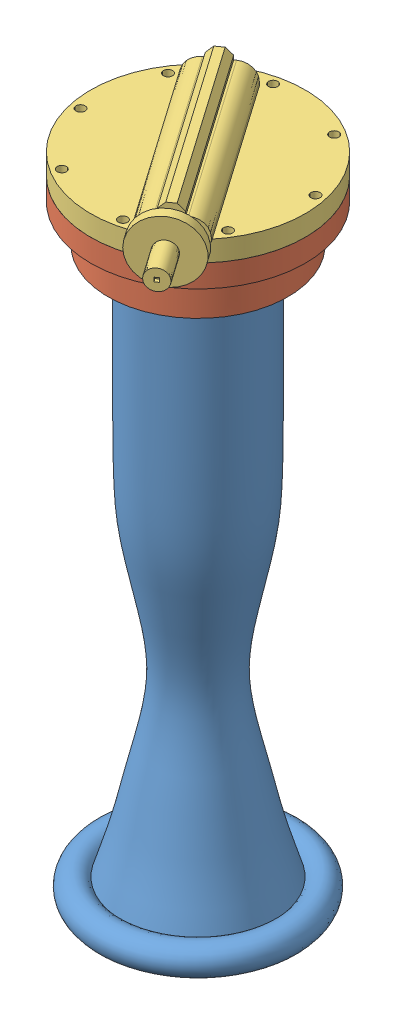
SolidWorks assembly LR101 Engine Assem, configuration Default. Lengths in mm.
Overall size (165.66 426.31 189.56).
4 component instances, 3 part files, 5 mates.
Components (placement in the parent):
- LR101 Engine-1: LR101 Engine [Default] at origin size (127.25 353.92 127.25)
  - Engine ID Profile (2) (1)-1: Engine ID Profile (2) (1) [Default] x (-1 0 0) z (0 0 1) size (127.25 353.92 127.25)
- LR101 Bottom Injector Plate-1: LR101 Bottom Injector Plate [Default] x (0.215085 0 0.976595) z (-0.976595 0 0.215085) size (133.35 37.46 133.35)
- LR101 TOP INJECTOR PLATE-1: LR101 TOP INJECTOR PLATE [Default] at (0 37.465 0) x (0.976595 0 -0.215085) z (0.215085 0 0.976595) size (133.35 38.1 164.73)
Mates (geometry in assembly coordinates):
- Concentric1: concentric aligned: circle of LR101 Engine-1/Engine ID Profile (2) (1)-1; circle of LR101 Bottom Injector Plate-1
- Coincident1: coincident anti-aligned: plane of LR101 Engine-1/Engine ID Profile (2) (1)-1 through (-76.2 0 50.8) normal (0 1 0); plane of LR101 Bottom Injector Plate-1 through (0 0 0) normal (0 -1 0)
- Coincident2: coincident anti-aligned: plane of LR101 Bottom Injector Plate-1 through (0 37.465 0) normal (0 1 0); plane of LR101 TOP INJECTOR PLATE-1 through (0 37.465 0) normal (0 -1 0)
- Concentric2: concentric aligned: cylinder of LR101 Bottom Injector Plate-1 through (0 37.465 0) axis (0 -1 0) radius 66.675; cylinder of LR101 TOP INJECTOR PLATE-1 through (0 50.165 0) axis (0 -1 0) radius 66.675
- Concentric3: concentric aligned: cylinder of LR101 Bottom Injector Plate-1 through (-32.996 0 51.6352) axis (0 1 0) radius 2.8575; cylinder of LR101 TOP INJECTOR PLATE-1 through (-32.996 37.465 51.6352) axis (0 1 0) radius 2.8575
